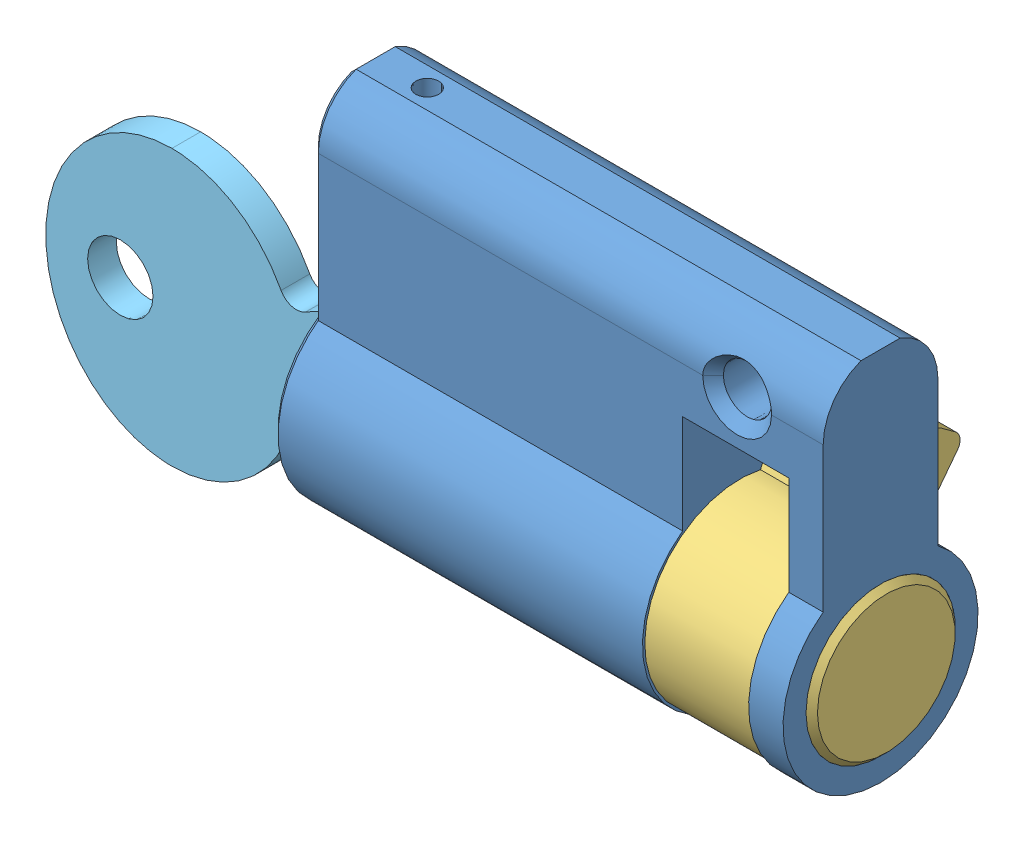
SolidWorks assembly lock_assembly_eg, configuration Default. Lengths in mm.
Overall size (72.78 39.24 18.44).
7 component instances, 5 part files, 0 mates.
Components (placement in the parent):
- cylinder_sub-assembly_e-1: cylinder_sub-assembly_e [Default] at origin size (44.5 32.7 17)
  - cylinder_d_one-pair_of_pins-1: cylinder_d_one-pair_of_pins [Default] at origin size (44.5 32.7 17)
  - upper_half_pin_y_cut_depth_2-1: upper_half_pin_y_cut_depth_2 [Default] at (5 15.25 0) x (1 0 0) z (0 -1 0) size (2 2 8)
- core_sub-assembly_g-1: core_sub-assembly_g [Default] at origin size (72.78 29.23 18.24)
  - core_c_one-pair_of_pins-1: core_c_one-pair_of_pins [Default] at origin size (45.22 22.49 18.24)
  - lower_half_pin_x-depth_2-1: lower_half_pin_x-depth_2 [Default] at (5 7.25 0) size (2.04 6.1 2.04)
  - key_f-1: key_f [Default] at (0 -2.25 0) x (1 0 0) z (0 -1 0) size (60.37 2.5 25.58)
